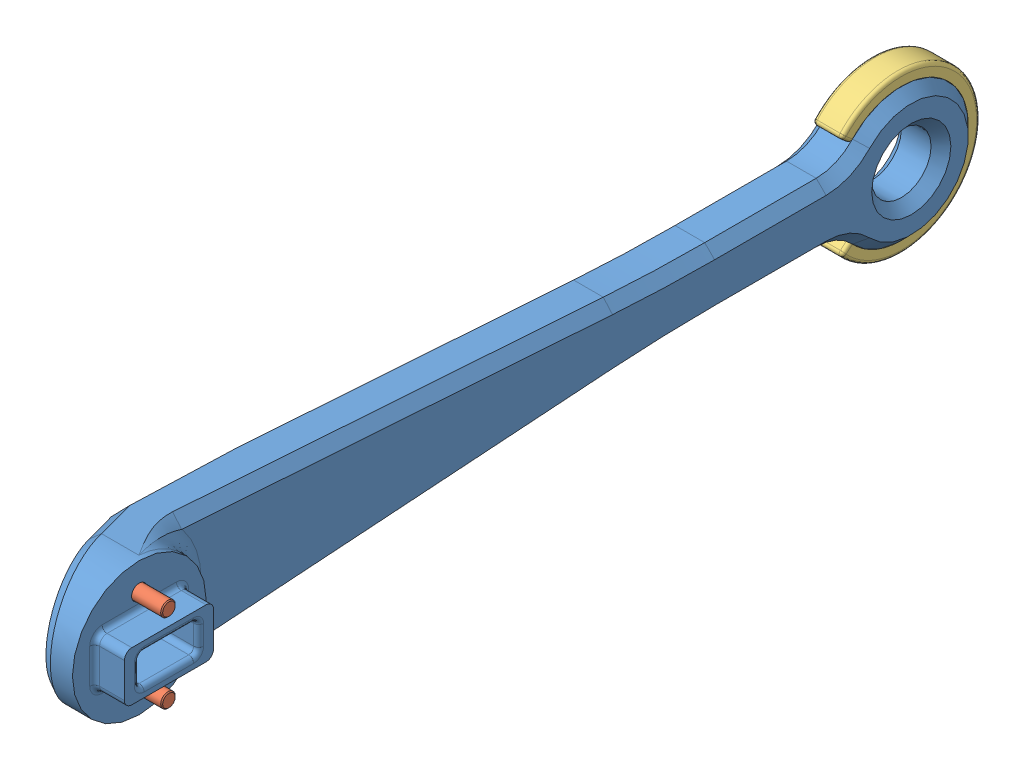
SolidWorks assembly _lower_leg, configuration Standard. Lengths in mm.
Overall size (24.5 32.92 189.4).
4 component instances, 3 part files, 7 mates.
Components (placement in the parent):
- lower_leg_solid-1: lower_leg_solid [Standard] at origin size (24.5 32.92 187)
- fastener_shcs_m3_12-1: fastener_shcs_m3_12 [Standard] at (3 -8 0) x (0 0 1) z (-1 0 0) size (5.5 5.5 15)
- fastener_shcs_m3_12-2: fastener_shcs_m3_12 [Standard] at (3 8 0) x (0 0 1) z (-1 0 0) size (5.5 5.5 15)
- foot_padding-1: foot_padding [Standard] at (0 0 -160) x (1 0 0) z (0 1 0) size (6.08 27.78 31.8)
Mates (geometry in assembly coordinates):
- Konzentrisch1: concentric anti-aligned: cylinder of lower_leg_solid-1 through (-5 8 0) axis (1 0 0) radius 1.55; cylinder of fastener_shcs_m3_12-2 through (-18.9199 8 0) axis (-1 0 0) radius 1.465
- Konzentrisch2: concentric anti-aligned: cylinder of lower_leg_solid-1 through (-5 -8 0) axis (1 0 0) radius 1.55; cylinder of fastener_shcs_m3_12-1 through (-18.9199 -8 0) axis (-1 0 0) radius 1.465
- Deckungsgleich1: coincident anti-aligned: plane of lower_leg_solid-1 through (3 8 0) normal (-1 0 0); plane of fastener_shcs_m3_12-2 through (3 10.75 0) normal (1 0 0)
- Deckungsgleich2: coincident anti-aligned: plane of lower_leg_solid-1 through (3 -8 0) normal (-1 0 0); plane of fastener_shcs_m3_12-1 through (3 -5.25 0) normal (1 0 0)
- Deckungsgleich3: coincident anti-aligned: line of lower_leg_solid-1 through (-6.225 0 -160) axis (1 0 0); line of foot_padding-1 through (3.3434 0 -160) axis (-1 0 0)
- Deckungsgleich4: coincident aligned: plane of foot_padding-1 through (0 0 -160) normal (0 1 0); plane of assembly through (0 0 0) normal (0 1 0)
- Deckungsgleich5: coincident aligned: plane of foot_padding-1 through (0 0 -160) normal (1 0 0); plane of assembly through (0 0 0) normal (1 0 0)
